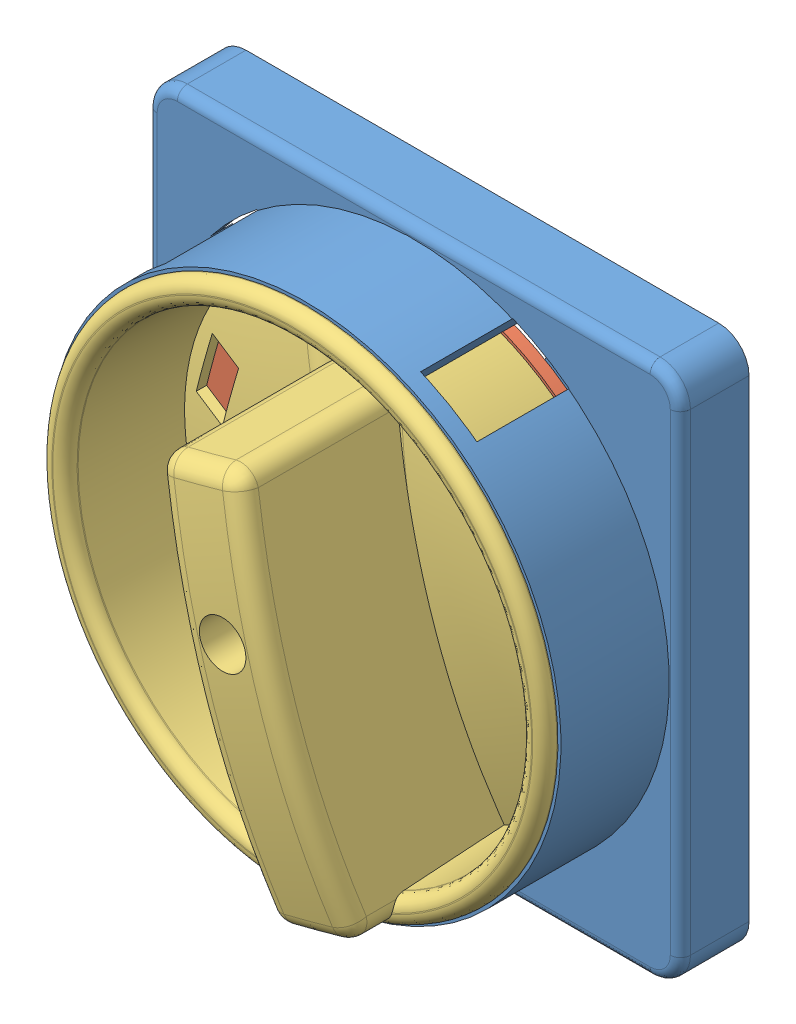
SolidWorks assembly switch1, configuration Default. Lengths in mm.
Overall size (77.74 77.74 32.66).
4 component instances, 4 part files, 5 mates.
Components (placement in the parent):
- cowling-1: cowling [Default] at (-46.9971 -34.9237 5.5665) size (67.06 67.06 22.25)
- indicator plate-1: indicator plate [Default] at (-13.4691 -1.3957 5.2617) size (58.93 58.93 11.13)
- switch dial-1: switch dial [Default] at (-13.4691 -1.3957 19.1809) x (0.258123 -0.966112 0) z (0 0 1) size (63.5 63.5 24.9)
- screw-1: screw [Default] at (-13.4691 -1.3957 22.9601) x (1 0 0) z (0 -1 0) size (5.59 15.21 5.59)
Mates (geometry in assembly coordinates):
- Coincident1: coincident anti-aligned: plane of cowling-1 through (-13.4691 -1.3957 3.8139) normal (0 0 1); plane of indicator plate-1 through (-13.4691 -1.3957 3.8139) normal (0 0 -1)
- Concentric1: concentric anti-aligned: circle of cowling-1; circle of indicator plate-1
- Concentric3: concentric anti-aligned: cylinder of cowling-1 through (-13.4691 -1.3957 3.8139) axis (0 0 1) radius 29.972; cone of switch dial-1 through (-13.4691 -1.3957 19.1809) axis (0 0 -1)
- Coincident2: coincident anti-aligned: plane of cowling-1 through (-13.4691 -1.3957 19.1809) normal (0 0 1); plane of switch dial-1 through (-13.4691 -1.3957 19.1809) normal (0 0 -1)
- Concentric4: concentric anti-aligned: circle of switch dial-1; circle of screw-1
